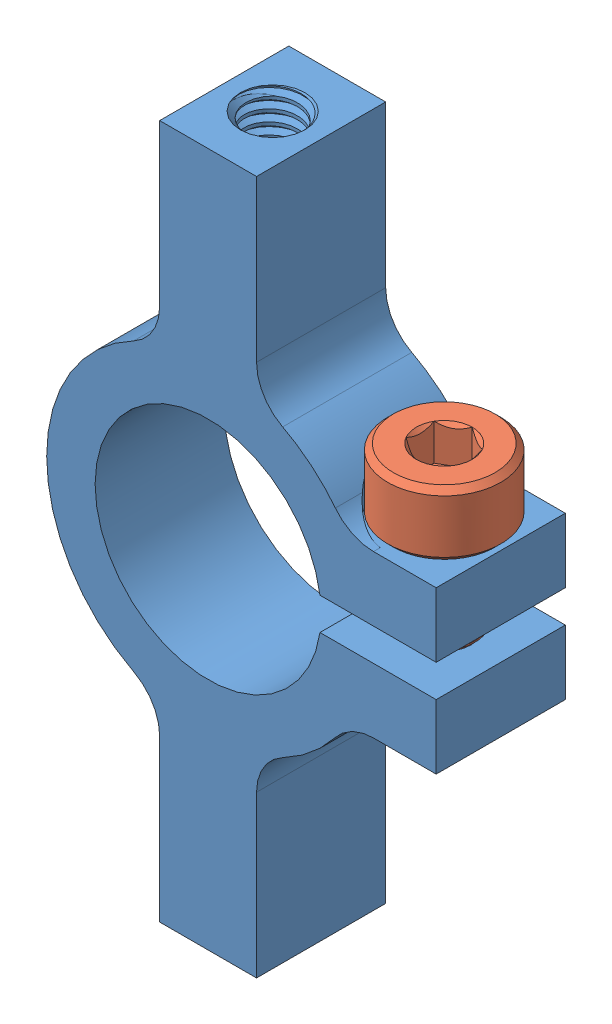
SolidWorks assembly 2-Side, 1-Post Clamping Mount (43mm Width, 14mm Bore) 1402-0043-0014, configuration Default. Lengths in mm.
Overall size (24.13 43.01 8).
2 component instances, 2 part files, 0 mates.
Components (placement in the parent):
- 1402-0043-0014 without hardware.step-1: 1402-0043-0014 without hardware.step [Default] at (-10.2331 3.9775 4.6446) x (0 -1 0) z (1 0 0) size (43.01 8 24.13)
- 2800-0004-0010.step-1: 2800-0004-0010.step [Default] at (0.3951 -1.0225 8.6446) size (7 14.01 7)
